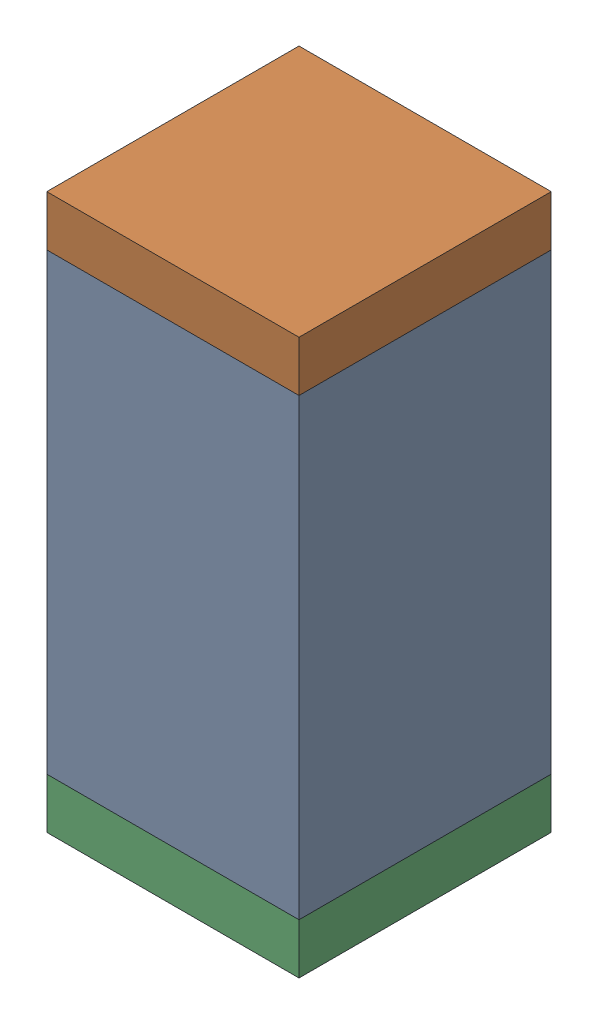
SolidWorks assembly C42, configuration Default. Lengths in mm.
Overall size (0.5 1.1 0.5).
6 component instances, 2 part files, 0 mates.
Components (placement in the parent):
- 791586336-1: 791586336 [Default] at (120.9 36.2 0) size (0.5 0.9 0.5)
  - Extruded_8-1: Extruded_8 [Default] at origin size (0.5 0.9 0.5)
- 810157360-1: 810157360 [Default] at (120.9 36.7 0) size (0.5 0.1 0.5)
  - Extruded_9-1: Extruded_9 [Default] at origin size (0.5 0.1 0.5)
- 810157360-2: 810157360 [Default] at (120.9 35.7 0) size (0.5 0.1 0.5)
  - Extruded_9-1: Extruded_9 [Default] at origin size (0.5 0.1 0.5)
